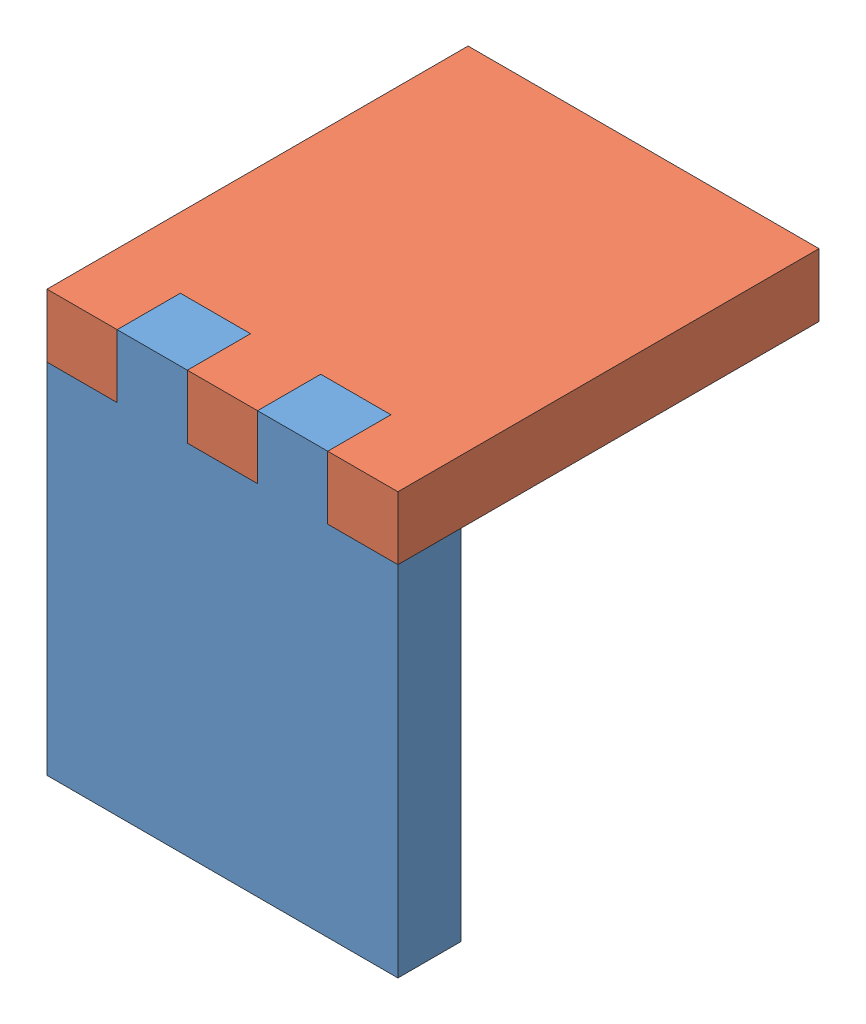
SolidWorks assembly FINGER JOINT EXPLODE, configuration Default. Lengths in mm.
Overall size (100 120 182.11).
2 component instances, 2 part files, 3 mates.
Components (placement in the parent):
- PART2-1: PART2 [Default] at origin size (100 120 18)
- PART1-1: PART1 [Default] at (0 120 -102) x (1 0 0) z (0 -1 0) size (100 120 18)
Mates (geometry in assembly coordinates):
- Coincident1: coincident anti-aligned: plane of PART2-1 through (0 120 0) normal (0 0 -1); plane of PART1-1 through (60 102 0) normal (0 0 1)
- Coincident2: coincident aligned: plane of PART2-1 through (60 120 18) normal (0 1 0); plane of PART1-1 through (0 120 18) normal (0 1 0)
- Coincident3: coincident: plane of PART2-1 through (100 0 18) normal (1 0 0); line of PART1-1 through (100 102 -102) axis (0 0 1)
